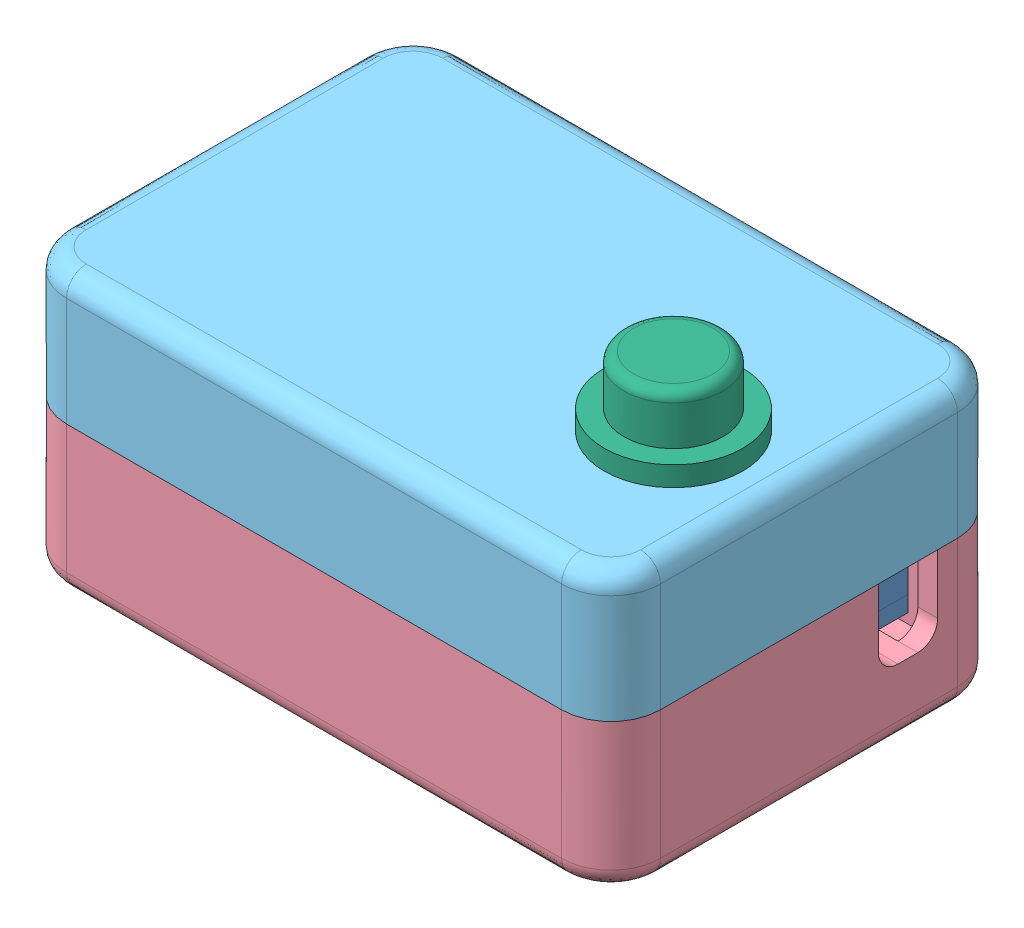
SolidWorks assembly 总装配体, configuration 默认. Lengths in mm.
Overall size (61.28 35.32 40).
6 component instances, 6 part files, 16 mates.
Components (placement in the parent):
- 3D_PCB_LED_ESP01S_2023-10-06-1: 3D_PCB_LED_ESP01S_2023-10-06 [默认] at (-31.8347 6 36.9453) x (1 0 0) z (0 1 0) size (50.28 30.06 17.5)
- 按钮-1: 按钮 [默认] at (-77.3523 13.3211 11.9734) size (7 21 7)
- 按钮2-1: 按钮2 [默认] at (-25.2766 9.35 2.5282) x (-1 0 0) z (0 0 -1) size (6 4 8)
- 底壳-1: 底壳 [默认] at origin size (60 22 40)
- 顶壳-1: 顶壳 [默认] at (0 28 0) x (1 0 0) z (0 0 -1) size (60 20 40)
- 键帽-1: 键帽 [默认] at (19.6004 28.3211 3.2902) size (14 7 14)
Mates (geometry in assembly coordinates):
- 重合1: coincident anti-aligned: plane of 3D_PCB_LED_ESP01S_2023-10-06-1 through (19.6004 12.3211 3.2902) normal (0 1 0); plane of 按钮-1 through (19.6004 12.3211 3.2902) normal (0 -1 0)
- 重合2: coincident anti-aligned: plane of 3D_PCB_LED_ESP01S_2023-10-06-1 through (-25.2766 9.35 2.5282) normal (-1 0 0); plane of 按钮2-1 through (-25.2766 9.35 0.5282) normal (1 0 0)
- 宽度2: width anti-aligned: plane of 按钮2-1 through (-28.2766 11.35 0.5282) normal (0 1 0); plane of 按钮2-1 through (-28.2766 7.35 0.5282) normal (0 -1 0); plane of 3D_PCB_LED_ESP01S_2023-10-06-1 through (-32.1307 8.6 1.0282) normal (0 -1 0); plane of 3D_PCB_LED_ESP01S_2023-10-06-1 through (-32.1307 10.1 1.0282) normal (0 1 0)
- 对称2: symmetric aligned: plane of 3D_PCB_LED_ESP01S_2023-10-06-1 through (-10.9503 7.6 -0.9718) normal (0 0 -1); plane of 3D_PCB_LED_ESP01S_2023-10-06-1 through (-10.9503 7.6 6.0282) normal (0 0 1); plane of 按钮2-1 through (-25.2766 9.35 2.5282) normal (0 0 -1)
- 重合3: coincident aligned: plane of 底壳-1 through (0 0 0) normal (0 0 1); plane of assembly through (0 0 0) normal (0 0 1)
- 重合4: coincident aligned: plane of 底壳-1 through (0 0 0) normal (0 1 0); plane of assembly through (0 0 0) normal (0 1 0)
- 重合5: coincident aligned: plane of 底壳-1 through (0 0 0) normal (1 0 0); plane of assembly through (0 0 0) normal (1 0 0)
- 平行1: parallel anti-aligned: plane of 3D_PCB_LED_ESP01S_2023-10-06-1 through (0.0669 6 -0.0076) normal (0 -1 0); plane of 底壳-1 through (1 4 15) normal (0 1 0)
- 距离1: distance = 2 mm anti-aligned: plane of 底壳-1 through (1 4 15) normal (0 1 0); plane of 3D_PCB_LED_ESP01S_2023-10-06-1 through (0.0669 6 -0.0076) normal (0 -1 0)
- 距离2: distance = 1 mm anti-aligned: plane of 3D_PCB_LED_ESP01S_2023-10-06-1 through (-24.822 6 -15) normal (0 0 -1); plane of 底壳-1 through (1 5 -16) normal (0 0 1)
- 距离3: distance = 1 mm anti-aligned: plane of 3D_PCB_LED_ESP01S_2023-10-06-1 through (25 6 -15) normal (1 0 0); plane of 底壳-1 through (26 -291584.25 -9) normal (-1 0 0)
- 重合8: coincident anti-aligned: plane of 底壳-1 through (0 15 0) normal (0 1 0); plane of 顶壳-1 through (0 15 0) normal (0 -1 0)
- 重合9: coincident aligned: plane of 底壳-1 through (-30 15 20) normal (0 0 1); plane of 顶壳-1 through (-30 15 20) normal (0 0 1)
- 重合10: coincident aligned: plane of 底壳-1 through (-30 15 -20) normal (-1 0 0); plane of 顶壳-1 through (-30 15 20) normal (-1 0 0)
- 重合11: coincident anti-aligned: plane of 按钮-1 through (19.6004 33.3211 3.2902) normal (0 1 0); plane of 键帽-1 through (19.6004 33.3211 3.2902) normal (0 -1 0)
- 同心1: concentric aligned: cylinder of 按钮-1 through (19.6004 33.3211 3.2902) axis (0 -1 0) radius 2.2; cylinder of 键帽-1 through (19.6004 33.3211 3.2902) axis (0 -1 0) radius 2.5
